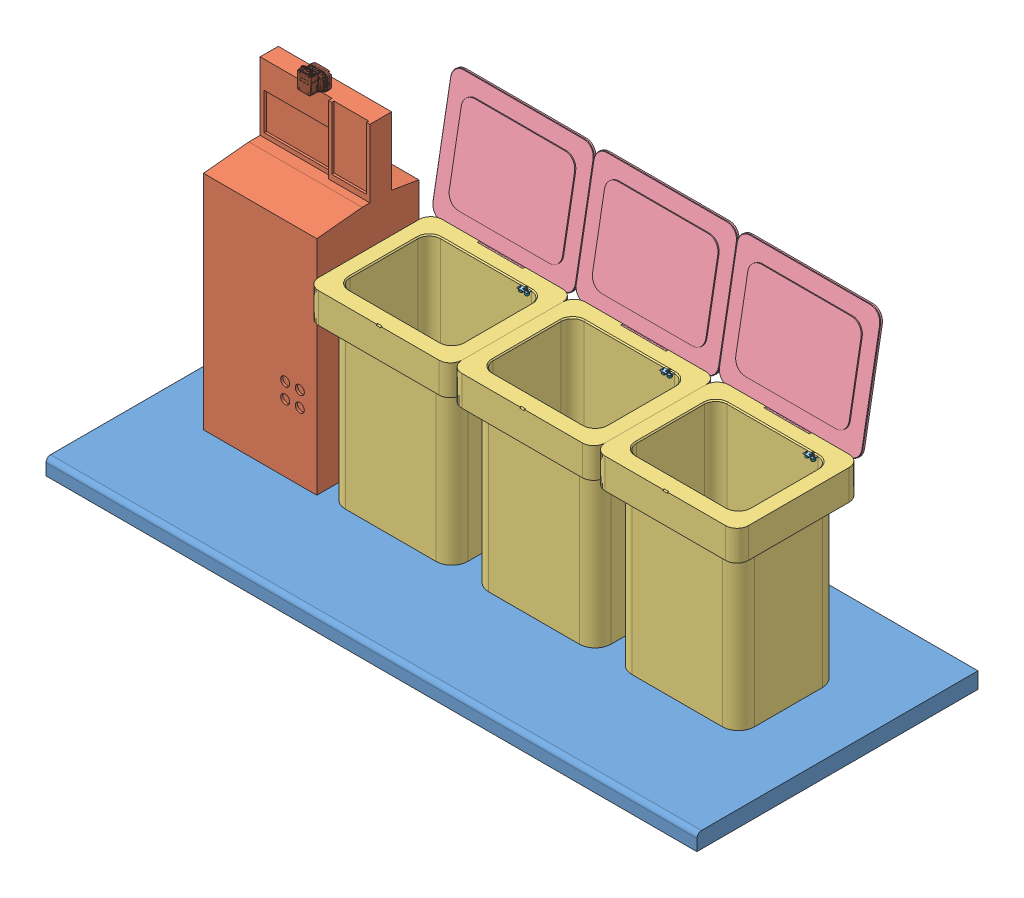
SolidWorks assembly Assembly, configuration Default. Lengths in mm.
Overall size (2871.39 1470.55 1240).
57 component instances, 11 part files, 19 mates.
Components (placement in the parent):
- Part1-1: Part1 [Default] at (146.0681 -328.7598 2280) size (2871.39 71 1240)
- Part2-1: Part2 [Default] at (-501.6104 -128.7598 2222.6142) size (500 1300 450)
- Bin_assembly-1: Bin_assembly [Default] at (-447.8879 -368.8317 1436.5357) size (632 1355.43 649.91)
  - bin_bottom-1: bin_bottom [Default] at (512.2775 60.0719 781.0786) size (632 828 545)
  - bin_flap-1: bin_flap [Default] at (512.2775 1124.6256 456.606) x (1 0 0) z (0 0.984355 -0.176195) size (632 20 545)
- Bin_assembly-2: Bin_assembly [Default] at (184.1121 -368.8317 1436.5357) size (632 1355.43 649.91)
  - bin_bottom-1: bin_bottom [Default] at (512.2775 60.0719 781.0786) size (632 828 545)
  - bin_flap-1: bin_flap [Default] at (512.2775 1124.6256 456.606) x (1 0 0) z (0 0.984355 -0.176195) size (632 20 545)
- Bin_assembly-3: Bin_assembly [Default] at (816.1121 -368.8317 1436.5357) size (632 1355.43 649.91)
  - bin_bottom-1: bin_bottom [Default] at (512.2775 60.0719 781.0786) size (632 828 545)
  - bin_flap-1: bin_flap [Default] at (512.2775 1124.6256 456.606) x (1 0 0) z (0 0.984355 -0.176195) size (632 20 545)
- HC-SR04 Ping Sensor-1: HC-SR04 Ping Sensor [Default] at (243.753 495.9902 2027.8642) x (0 0 -1) z (0 -1 0) size (25.18 45 18.07)
  - PCB-1: PCB [Default] at origin size (20.5 45 1.75)
  - Transducer-1: Transducer [Default] at (0 -13.16 13.25) x (1 0 0) z (0 -1 0) size (15.88 12 15.88)
  - Transducer-2: Transducer [Default] at (0 12.34 13.25) x (1 0 0) z (0 -1 0) size (15.88 12 15.88)
  - 3 Pin Header 90 Degree-1: 3 Pin Header 90 Degree [Default] at (8.4275 0 -1.25) x (-1 0 0) z (0 -1 0) size (8 7.82 10)
  - 14 Pin SMT-1: 14 Pin SMT [Default] at (-0.35 -18.5 -0.85) x (0 -1 0) z (1 0 0) size (6 1.6 8.8)
  - 14 Pin SMT-2: 14 Pin SMT [Default] at (0 -0.3826 -0.85) x (1 0 0) z (0 1 0) size (6 1.6 8.8)
  - 14 Pin SMT-3: 14 Pin SMT [Default] at (0 17.5274 -0.85) x (1 0 0) z (0 1 0) size (6 1.6 8.8)
  - Cap1 SMT-1: Cap1 SMT [Default] at (-1.755 7.4774 -0.9689) x (0 1 0) z (-1 0 0) size (4.5 1.84 1.75)
  - Cap1 SMT-2: Cap1 SMT [Default] at (6.835 7.4774 -0.9689) x (0 1 0) z (-1 0 0) size (4.5 1.84 1.75)
  - Cap1 SMT-3: Cap1 SMT [Default] at (-6.835 7.4774 -0.9689) x (0 1 0) z (-1 0 0) size (4.5 1.84 1.75)
  - Cap1 SMT-4: Cap1 SMT [Default] at (4.295 7.4774 -0.9689) x (0 1 0) z (-1 0 0) size (4.5 1.84 1.75)
  - Cap1 SMT-5: Cap1 SMT [Default] at (1.755 7.4774 -0.9689) x (0 1 0) z (-1 0 0) size (4.5 1.84 1.75)
  - Cap1 SMT-6: Cap1 SMT [Default] at (-4.295 7.4774 -0.9689) x (0 1 0) z (-1 0 0) size (4.5 1.84 1.75)
  - HC-SR04 Crystal-1: HC-SR04 Crystal [Default] at (-8.3 0 1.75) x (0 -1 0) z (0 0 1) size (10 3.5 2.7)
- HC-SR04 Ping Sensor-2: HC-SR04 Ping Sensor [Default] at (873.3479 495.9902 2027.8642) x (0 0 -1) z (0 -1 0) size (25.18 45 18.07)
  - PCB-1: PCB [Default] at origin size (20.5 45 1.75)
  - Transducer-1: Transducer [Default] at (0 -13.16 13.25) x (1 0 0) z (0 -1 0) size (15.88 12 15.88)
  - Transducer-2: Transducer [Default] at (0 12.34 13.25) x (1 0 0) z (0 -1 0) size (15.88 12 15.88)
  - 3 Pin Header 90 Degree-1: 3 Pin Header 90 Degree [Default] at (8.4275 0 -1.25) x (-1 0 0) z (0 -1 0) size (8 7.82 10)
  - 14 Pin SMT-1: 14 Pin SMT [Default] at (-0.35 -18.5 -0.85) x (0 -1 0) z (1 0 0) size (6 1.6 8.8)
  - 14 Pin SMT-2: 14 Pin SMT [Default] at (0 -0.3826 -0.85) x (1 0 0) z (0 1 0) size (6 1.6 8.8)
  - 14 Pin SMT-3: 14 Pin SMT [Default] at (0 17.5274 -0.85) x (1 0 0) z (0 1 0) size (6 1.6 8.8)
  - Cap1 SMT-1: Cap1 SMT [Default] at (-1.755 7.4774 -0.9689) x (0 1 0) z (-1 0 0) size (4.5 1.84 1.75)
  - Cap1 SMT-2: Cap1 SMT [Default] at (6.835 7.4774 -0.9689) x (0 1 0) z (-1 0 0) size (4.5 1.84 1.75)
  - Cap1 SMT-3: Cap1 SMT [Default] at (-6.835 7.4774 -0.9689) x (0 1 0) z (-1 0 0) size (4.5 1.84 1.75)
  - Cap1 SMT-4: Cap1 SMT [Default] at (4.295 7.4774 -0.9689) x (0 1 0) z (-1 0 0) size (4.5 1.84 1.75)
  - Cap1 SMT-5: Cap1 SMT [Default] at (1.755 7.4774 -0.9689) x (0 1 0) z (-1 0 0) size (4.5 1.84 1.75)
  - Cap1 SMT-6: Cap1 SMT [Default] at (-4.295 7.4774 -0.9689) x (0 1 0) z (-1 0 0) size (4.5 1.84 1.75)
  - HC-SR04 Crystal-1: HC-SR04 Crystal [Default] at (-8.3 0 1.75) x (0 -1 0) z (0 0 1) size (10 3.5 2.7)
- HC-SR04 Ping Sensor-3: HC-SR04 Ping Sensor [Default] at (1506.2718 494.2402 2027.8642) x (0 0 -1) z (0 -1 0) size (25.18 45 18.07)
  - PCB-1: PCB [Default] at origin size (20.5 45 1.75)
  - Transducer-1: Transducer [Default] at (0 -13.16 13.25) x (1 0 0) z (0 -1 0) size (15.88 12 15.88)
  - Transducer-2: Transducer [Default] at (0 12.34 13.25) x (1 0 0) z (0 -1 0) size (15.88 12 15.88)
  - 3 Pin Header 90 Degree-1: 3 Pin Header 90 Degree [Default] at (8.4275 0 -1.25) x (-1 0 0) z (0 -1 0) size (8 7.82 10)
  - 14 Pin SMT-1: 14 Pin SMT [Default] at (-0.35 -18.5 -0.85) x (0 -1 0) z (1 0 0) size (6 1.6 8.8)
  - 14 Pin SMT-2: 14 Pin SMT [Default] at (0 -0.3826 -0.85) x (1 0 0) z (0 1 0) size (6 1.6 8.8)
  - 14 Pin SMT-3: 14 Pin SMT [Default] at (0 17.5274 -0.85) x (1 0 0) z (0 1 0) size (6 1.6 8.8)
  - Cap1 SMT-1: Cap1 SMT [Default] at (-1.755 7.4774 -0.9689) x (0 1 0) z (-1 0 0) size (4.5 1.84 1.75)
  - Cap1 SMT-2: Cap1 SMT [Default] at (6.835 7.4774 -0.9689) x (0 1 0) z (-1 0 0) size (4.5 1.84 1.75)
  - Cap1 SMT-3: Cap1 SMT [Default] at (-6.835 7.4774 -0.9689) x (0 1 0) z (-1 0 0) size (4.5 1.84 1.75)
  - Cap1 SMT-4: Cap1 SMT [Default] at (4.295 7.4774 -0.9689) x (0 1 0) z (-1 0 0) size (4.5 1.84 1.75)
  - Cap1 SMT-5: Cap1 SMT [Default] at (1.755 7.4774 -0.9689) x (0 1 0) z (-1 0 0) size (4.5 1.84 1.75)
  - Cap1 SMT-6: Cap1 SMT [Default] at (-4.295 7.4774 -0.9689) x (0 1 0) z (-1 0 0) size (4.5 1.84 1.75)
  - HC-SR04 Crystal-1: HC-SR04 Crystal [Default] at (-8.3 0 1.75) x (0 -1 0) z (0 0 1) size (10 3.5 2.7)
- vs70.stp-2: vs70.stp [Default] at (-505.4731 1009.8797 2219.6725) x (1 0 0) z (0 -0.034899 -0.999391) size (91.8 98.2 77.71)
Mates (geometry in assembly coordinates):
- Coincident1: coincident: point of assembly; point of Part1-1; point of Part2-1
- Coincident2: coincident anti-aligned: plane of Part1-1 through (146.0681 -328.7598 2280) normal (0 1 0); plane of Bin_assembly-1/bin_bottom-1 through (-135.6104 -328.7598 2367.6142) normal (0 -1 0)
- Coincident3: coincident anti-aligned: plane of Part1-1 through (146.0681 -328.7598 2280) normal (0 1 0); plane of Bin_assembly-2/bin_bottom-1 through (496.3896 -328.7598 2367.6142) normal (0 -1 0)
- Coincident4: coincident anti-aligned: plane of Part1-1 through (146.0681 -328.7598 2280) normal (0 1 0); plane of Bin_assembly-3/bin_bottom-1 through (1128.3896 -328.7598 2367.6142) normal (0 -1 0)
- Coincident5: coincident aligned: line of Part1-1 through (1635.1366 -328.7598 1997.6142) axis (-1 0 0); line of Bin_assembly-1/bin_bottom-1 through (264.3896 -328.7598 1997.6142) axis (-1 0 0)
- Coincident6: coincident anti-aligned: line of Bin_assembly-1/bin_bottom-1 through (380.3896 499.2402 2440.1142) axis (0 0 -1); line of Bin_assembly-2/bin_bottom-1 through (380.3896 499.2402 1995.1142) axis (0 0 1)
- Coincident7: coincident aligned: line of Part1-1 through (1635.1366 -328.7598 1997.6142) axis (-1 0 0); line of Bin_assembly-2/bin_bottom-1 through (896.3896 -328.7598 1997.6142) axis (-1 0 0)
- Coincident8: coincident anti-aligned: line of Bin_assembly-2/bin_bottom-1 through (1012.3896 499.2402 2440.1142) axis (0 0 -1); line of Bin_assembly-3/bin_bottom-1 through (1012.3896 499.2402 1995.1142) axis (0 0 1)
- Coincident9: coincident aligned: line of Part1-1 through (1635.1366 -328.7598 1997.6142) axis (-1 0 0); line of Bin_assembly-3/bin_bottom-1 through (1528.3896 -328.7598 1997.6142) axis (-1 0 0)
- Coincident11: coincident anti-aligned: plane of Part1-1 through (146.0681 -328.7598 2280) normal (0 1 0); plane of Part2-1 through (-501.6104 -328.7598 2222.6142) normal (0 -1 0)
- Coincident13: coincident anti-aligned: line of Part1-1 through (-751.6104 -328.7598 2562.3858) axis (0 0 -1); line of Part2-1 through (-751.6104 -328.7598 1997.6142) axis (0 0 1)
- Coincident14: coincident anti-aligned: plane of Part2-1 through (-251.6104 -328.7598 2447.6142) normal (1 0 0); plane of Bin_assembly-1/bin_bottom-1 through (-251.6104 499.2402 1995.1142) normal (-1 0 0)
- Coincident19: coincident anti-aligned: plane of Bin_assembly-1/bin_bottom-1 through (-135.6104 491.2402 2017.6142) normal (0 0 1); plane of HC-SR04 Ping Sensor-1/PCB-1 through (266.253 494.2402 2017.6142) normal (0 0 -1)
- Coincident20: coincident anti-aligned: line of Bin_assembly-1/bin_bottom-1 through (264.3896 494.2402 2017.6142) axis (-1 0 0); line of HC-SR04 Ping Sensor-1/PCB-1 through (221.253 494.2402 2017.6142) axis (1 0 0)
- Coincident21: coincident anti-aligned: plane of Bin_assembly-2/bin_bottom-1 through (496.3896 491.2402 2017.6142) normal (0 0 1); plane of HC-SR04 Ping Sensor-2/PCB-1 through (895.8479 494.2402 2017.6142) normal (0 0 -1)
- Coincident22: coincident anti-aligned: line of Bin_assembly-2/bin_bottom-1 through (896.3896 494.2402 2017.6142) axis (-1 0 0); line of HC-SR04 Ping Sensor-2/PCB-1 through (850.8479 494.2402 2017.6142) axis (1 0 0)
- Parallel4: parallel anti-aligned: plane of Bin_assembly-3/bin_bottom-1 through (1128.3896 491.2402 2017.6142) normal (0 0 1); plane of HC-SR04 Ping Sensor-3/PCB-1 through (1528.7718 492.4902 2017.6142) normal (0 0 -1)
- Coincident23: coincident anti-aligned: line of Bin_assembly-3/bin_bottom-1 through (1528.3896 494.2402 2017.6142) axis (-1 0 0); line of HC-SR04 Ping Sensor-3/PCB-1 through (1483.7718 494.2402 2017.6142) axis (1 0 0)
- Coincident24: coincident anti-aligned: plane of Part2-1 through (-501.6104 971.2402 2222.6142) normal (0 1 0); plane of vs70.stp-2 through (-505.4731 971.2402 2179.7016) normal (0 -1 0)
